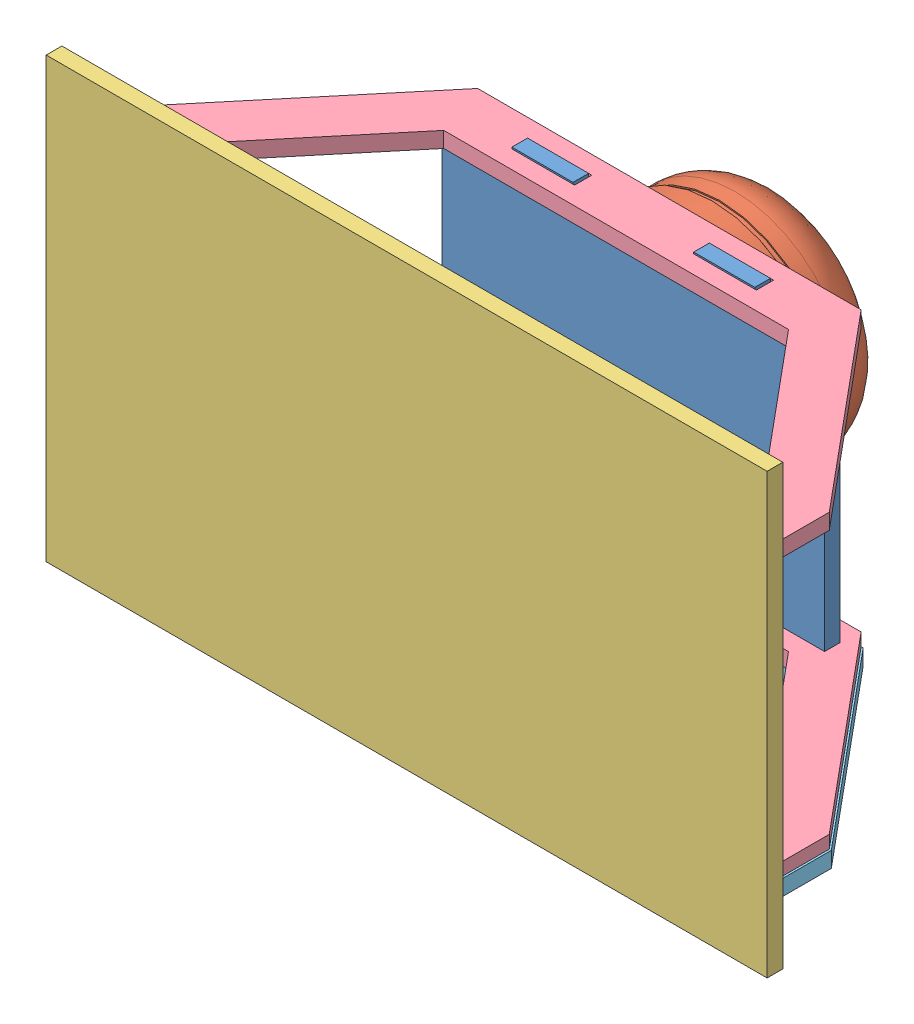
SolidWorks assembly AssemMetalCNC, configuration Défaut. Lengths in mm.
Overall size (230.18 140 121.55).
6 component instances, 5 part files, 9 mates.
Components (placement in the parent):
- floor-1: floor [Défaut] at (4.3607 1.0902 122) size (122 95 5)
- LIDAR-1: LIDAR [Default] at (5.9188 4.8664 122) x (1 0 0) z (0 1 0) size (75.7 40.8 75.7)
- Plate-with-spaces-COPY-1: Plate-with-spaces-COPY [Défaut] at (7.788 5.4894 197.75) size (230 140 5)
- leg-CNC-3: leg-CNC [Défaut] at (4.6107 43.0902 197.75) x (1 0 0) z (0 1 0) size (224 82 5)
- leg-CNC-4: leg-CNC [Défaut] at (4.6107 -45.9098 197.75) x (1 0 0) z (0 1 0) size (224 82 5)
- leg2-CNC-1: leg2-CNC [Défaut] at (5.2562 -50.007 197.75) x (1 0 0) z (0 1 0) size (224 82 5)
Mates (geometry in assembly coordinates):
- Coincident2: coincident anti-aligned: plane of Plate-with-spaces-COPY-1 through (7.788 5.4894 197.75) normal (0 0 -1); plane of leg-CNC-3 through (-107.3893 48.0902 197.75) normal (0 0 1)
- Coincident3: coincident anti-aligned: plane of Plate-with-spaces-COPY-1 through (7.788 5.4894 197.75) normal (0 0 -1); plane of leg-CNC-4 through (116.6107 -40.9098 197.75) normal (0 0 1)
- Coincident5: coincident anti-aligned: plane of floor-1 through (4.3607 1.0902 127) normal (0 0 1); plane of leg-CNC-3 through (43.6107 48.0902 127) normal (0 0 -1)
- Coincident6: coincident anti-aligned: plane of floor-1 through (-14.8893 43.0902 127) normal (0 1 0); plane of leg-CNC-3 through (4.6107 43.0902 197.75) normal (0 -1 0)
- Coincident9: coincident anti-aligned: plane of floor-1 through (23.6107 -46.4098 127) normal (-1 0 0); plane of leg-CNC-4 through (23.6107 -40.9098 121.5) normal (1 0 0)
- Coincident10: coincident anti-aligned: plane of floor-1 through (-14.8893 -40.9098 127) normal (0 -1 0); plane of leg-CNC-4 through (4.6107 -40.9098 197.75) normal (0 1 0)
- Coincident11: coincident anti-aligned: plane of floor-1 through (4.3607 1.0902 122) normal (0 0 -1); plane of LIDAR-1 through (5.9188 4.8664 122) normal (0 0 1)
- Coincident12: coincident anti-aligned: plane of floor-1 through (-34.3893 43.0902 127) normal (-1 0 0); plane of leg-CNC-3 through (-34.3893 48.0902 121.5) normal (1 0 0)
- Coincident13: coincident anti-aligned: plane of Plate-with-spaces-COPY-1 through (7.788 5.4894 197.75) normal (0 0 -1); plane of leg2-CNC-1 through (-106.7438 -45.007 197.75) normal (0 0 1)
